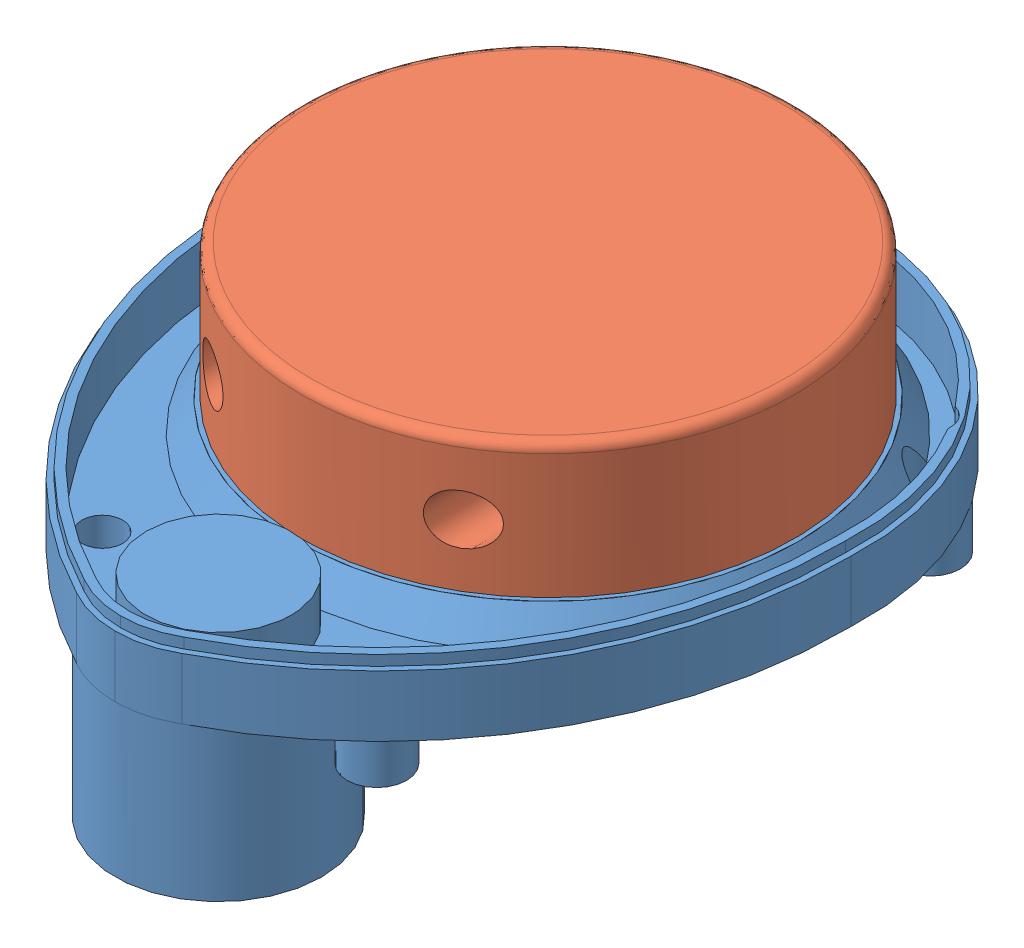
SolidWorks assembly Assem1, configuration Default. Lengths in mm.
Overall size (96.85 53.25 115.02).
2 component instances, 2 part files, 3 mates.
Components (placement in the parent):
- lidar-body-1: lidar-body [Default] at (0 24.25 0) x (1 0 0) z (0 1 0) size (96.85 115.02 35.65)
- lidar-turrent-1: lidar-turrent [Default] at (200 31.85 -69.12) size (78.6 21.4 78.6)
Mates (geometry in assembly coordinates):
- Coincident1: coincident anti-aligned: plane of lidar-body-1 through (200 0 -16.5) normal (0 -1 0); plane of assembly through (0 0 0) normal (0 1 0)
- Coincident3: coincident anti-aligned: plane of lidar-body-1 through (200 31.85 -69.12) normal (0 1 0); plane of lidar-turrent-1 through (200 31.85 -69.12) normal (0 -1 0)
- Concentric1: concentric anti-aligned: circle of lidar-body-1; cylinder of lidar-turrent-1 through (200 53.25 -69.12) axis (0 -1 0) radius 39.3
